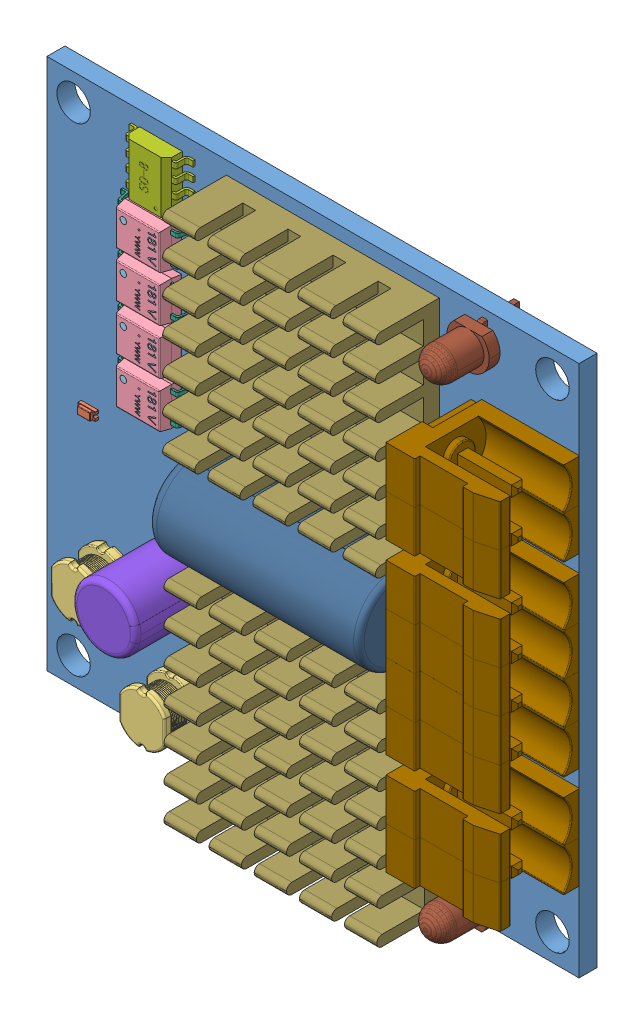
SolidWorks assembly 电机驱动, configuration 默认. Lengths in mm.
Overall size (50.06 50 12.7).
67 component instances, 13 part files, 0 mates.
Components (placement in the parent):
- 3D Motor_Driver_22.step-1: 3D Motor_Driver_22.step [默认] at origin size (50.06 50 12.7)
  - Board.step-1: Board.step [默认] at origin size (50 50 1.69)
    - Open CASCADE STEP translator 6.8 1.1.1.step-1: Open CASCADE STEP translator 6.8 1.1.1.step [默认] at (0 0 -1.6914) size (50 50 1.69)
  - LED2.step-1: LED2.step [默认] at origin size (1.62 0.8 0.6)
    - User_Library-led_0603LED0603_red.step-1: User_Library-led_0603LED0603_red.step [默认] at (4.0385 23.2409 0) x (1 0 0) z (0 0 1) size (1.62 0.8 0.6)
  - L2.step-1: L2.step [默认] at origin size (4.31 4.81 3.5)
    - ____CD43NP.step-1: ____CD43NP.step [默认] at (12.3951 3.937 0) x (1 0 0) z (0 -1 0) size (4.31 3.5 4.81)
  - L1.step-1: L1.step [默认] at origin size (4.31 4.81 3.5)
    - ____CD43NP.step-1: ____CD43NP.step [默认] at (5.9435 10.9221 0) x (1 0 0) z (0 -1 0) size (4.31 3.5 4.81)
  - OP4.step-1: OP4.step [默认] at origin size (7 3.6 2.1)
    - HCPL-181.step-1: HCPL-181.step [默认] at (10.6172 32.7835 0.1) x (0 -1 0) z (0 0 1) size (3.6 7 2.1)
      - User_Library-HCPL-181-1_K_X_F6rper_1.step-1: User_Library-HCPL-181-1_K_X_F6rper_1.step [默认] x (-1 0 0) z (0 0 1) size (3.6 4.4 2)
      - User_Library-HCPL-181-1_Beschriftung_1.step-1: User_Library-HCPL-181-1_Beschriftung_1.step [默认] x (-1 0 0) z (0 0 1) size (2.65 3.38 0.06)
      - User_Library-HCPL-181-1_Pins_1.step-1: User_Library-HCPL-181-1_Pins_1.step [默认] at (-1.27 0 0) x (-1 0 0) z (0 0 1) size (0.4 1.4 1.2)
      - User_Library-HCPL-181-1_Pins_1.step-2: User_Library-HCPL-181-1_Pins_1.step [默认] at (1.27 0 0) x (-1 0 0) z (0 0 1) size (0.4 1.4 1.2)
      - User_Library-HCPL-181-1_Pins_1.step-3: User_Library-HCPL-181-1_Pins_1.step [默认] at (1.27 0 0) size (0.4 1.4 1.2)
      - User_Library-HCPL-181-1_Pins_1.step-4: User_Library-HCPL-181-1_Pins_1.step [默认] at (-1.27 0 0) size (0.4 1.4 1.2)
  - OP3.step-1: OP3.step [默认] at origin size (7 3.6 2.1)
    - HCPL-181.step-1: HCPL-181.step [默认] at (10.6172 41.402 0.1) x (0 -1 0) z (0 0 1) size (3.6 7 2.1)
      - User_Library-HCPL-181-1_K_X_F6rper_1.step-1: User_Library-HCPL-181-1_K_X_F6rper_1.step [默认] x (-1 0 0) z (0 0 1) size (3.6 4.4 2)
      - User_Library-HCPL-181-1_Beschriftung_1.step-1: User_Library-HCPL-181-1_Beschriftung_1.step [默认] x (-1 0 0) z (0 0 1) size (2.65 3.38 0.06)
      - User_Library-HCPL-181-1_Pins_1.step-1: User_Library-HCPL-181-1_Pins_1.step [默认] at (-1.27 0 0) x (-1 0 0) z (0 0 1) size (0.4 1.4 1.2)
      - User_Library-HCPL-181-1_Pins_1.step-2: User_Library-HCPL-181-1_Pins_1.step [默认] at (1.27 0 0) x (-1 0 0) z (0 0 1) size (0.4 1.4 1.2)
      - User_Library-HCPL-181-1_Pins_1.step-3: User_Library-HCPL-181-1_Pins_1.step [默认] at (1.27 0 0) size (0.4 1.4 1.2)
      - User_Library-HCPL-181-1_Pins_1.step-4: User_Library-HCPL-181-1_Pins_1.step [默认] at (-1.27 0 0) size (0.4 1.4 1.2)
  - OP2.step-1: OP2.step [默认] at origin size (7 3.6 2.1)
    - HCPL-181.step-1: HCPL-181.step [默认] at (10.6172 28.4743 0.1) x (0 -1 0) z (0 0 1) size (3.6 7 2.1)
      - User_Library-HCPL-181-1_K_X_F6rper_1.step-1: User_Library-HCPL-181-1_K_X_F6rper_1.step [默认] x (-1 0 0) z (0 0 1) size (3.6 4.4 2)
      - User_Library-HCPL-181-1_Beschriftung_1.step-1: User_Library-HCPL-181-1_Beschriftung_1.step [默认] x (-1 0 0) z (0 0 1) size (2.65 3.38 0.06)
      - User_Library-HCPL-181-1_Pins_1.step-1: User_Library-HCPL-181-1_Pins_1.step [默认] at (-1.27 0 0) x (-1 0 0) z (0 0 1) size (0.4 1.4 1.2)
      - User_Library-HCPL-181-1_Pins_1.step-2: User_Library-HCPL-181-1_Pins_1.step [默认] at (1.27 0 0) x (-1 0 0) z (0 0 1) size (0.4 1.4 1.2)
      - User_Library-HCPL-181-1_Pins_1.step-3: User_Library-HCPL-181-1_Pins_1.step [默认] at (1.27 0 0) size (0.4 1.4 1.2)
      - User_Library-HCPL-181-1_Pins_1.step-4: User_Library-HCPL-181-1_Pins_1.step [默认] at (-1.27 0 0) size (0.4 1.4 1.2)
  - OP1.step-1: OP1.step [默认] at origin size (7 3.6 2.1)
    - HCPL-181.step-1: HCPL-181.step [默认] at (10.6172 37.0928 0.1) x (0 -1 0) z (0 0 1) size (3.6 7 2.1)
      - User_Library-HCPL-181-1_K_X_F6rper_1.step-1: User_Library-HCPL-181-1_K_X_F6rper_1.step [默认] x (-1 0 0) z (0 0 1) size (3.6 4.4 2)
      - User_Library-HCPL-181-1_Beschriftung_1.step-1: User_Library-HCPL-181-1_Beschriftung_1.step [默认] x (-1 0 0) z (0 0 1) size (2.65 3.38 0.06)
      - User_Library-HCPL-181-1_Pins_1.step-1: User_Library-HCPL-181-1_Pins_1.step [默认] at (-1.27 0 0) x (-1 0 0) z (0 0 1) size (0.4 1.4 1.2)
      - User_Library-HCPL-181-1_Pins_1.step-2: User_Library-HCPL-181-1_Pins_1.step [默认] at (1.27 0 0) x (-1 0 0) z (0 0 1) size (0.4 1.4 1.2)
      - User_Library-HCPL-181-1_Pins_1.step-3: User_Library-HCPL-181-1_Pins_1.step [默认] at (1.27 0 0) size (0.4 1.4 1.2)
      - User_Library-HCPL-181-1_Pins_1.step-4: User_Library-HCPL-181-1_Pins_1.step [默认] at (-1.27 0 0) size (0.4 1.4 1.2)
  - IC1.step-1: IC1.step [默认] at origin size (6 4.9 1.7)
    - SO-8.step-1: SO-8.step [默认] at (10.9199 46.3812 0) x (0 1 0) z (0 0 1) size (4.9 6 1.7)
  - C20.step-1: C20.step [默认] at origin size (6.01 6 9.5)
    - ____6x7.step-1: ____6x7.step [默认] at (12.4205 13.9445 0.1) x (-1 0 0) z (0 0 1) size (6.01 6 9.5)
  - J1.step-1: J1.step [默认] at origin size (10.21 15.84 12.5)
    - HT396-1.step-1: HT396-1.step [默认] at (39.8577 21.0653 0) x (0 1 0) z (1 0 0) size (3.96 12.5 10.21)
    - HT396-1.step-2: HT396-1.step [默认] at (39.8577 17.1065 0) x (0 1 0) z (1 0 0) size (3.96 12.5 10.21)
    - HT396-1.step-3: HT396-1.step [默认] at (39.8577 28.9853 0) x (0 1 0) z (1 0 0) size (3.96 12.5 10.21)
    - HT396-1.step-4: HT396-1.step [默认] at (39.8577 25.0265 0) x (0 1 0) z (1 0 0) size (3.96 12.5 10.21)
  - P1.step-1: P1.step [默认] at origin size (10.21 7.92 12.5)
    - HT396-1.step-1: HT396-1.step [默认] at (39.8577 38.5553 0) x (0 1 0) z (1 0 0) size (3.96 12.5 10.21)
    - HT396-1.step-2: HT396-1.step [默认] at (39.8577 34.5965 0) x (0 1 0) z (1 0 0) size (3.96 12.5 10.21)
  - CN1.step-1: CN1.step [默认] at origin
    - User_Library-PLD-xxPLD-10.step-1: User_Library-PLD-xxPLD-10.step [默认] at (2.6012 42.1394 0) x (0 -1 0) z (0 0 1) (suppressed, hidden)
  - C14.step-1: C14.step [默认] at origin size (21.14 8.01 10)
    - ____8x20.step-1: ____8x20.step [默认] at (37.517 24.9779 4.2) x (0 -1 0) z (-1 0 0) size (8.01 10 21.14)
  - P4.step-1: P4.step [默认] at origin size (10.21 7.92 12.5)
    - HT396-1.step-1: HT396-1.step [默认] at (39.8577 7.5365 0) x (0 1 0) z (1 0 0) size (3.96 12.5 10.21)
    - HT396-1.step-2: HT396-1.step [默认] at (39.8577 11.4953 0) x (0 1 0) z (1 0 0) size (3.96 12.5 10.21)
  - grLED1.step-1: grLED1.step [默认] at origin size (4 3.53 8.57)
    - ____1.step-1: ____1.step [默认] at (41.1606 49.0007 0.2) x (0 -1 0) z (-1 0 0) size (3.53 8.57 4)
  - grLED2.step-1: grLED2.step [默认] at origin size (4 3.53 8.57)
    - ____1.step-1: ____1.step [默认] at (41.1354 0.9865 0.2) x (0 1 0) z (1 0 0) size (3.53 8.57 4)
  - Free-Models.step-1: Free-Models.step [默认] at origin size (20.13 49.97 6)
    - 20x20x6____.step-1: 20x20x6____.step [默认] at (18.067 29.972 2.7) x (0 1 0) z (1 0 0) size (20 6 20)
    - 20x20x6____.step-2: 20x20x6____.step [默认] at (18.194 0 2.7) x (0 1 0) z (1 0 0) size (20 6 20)
